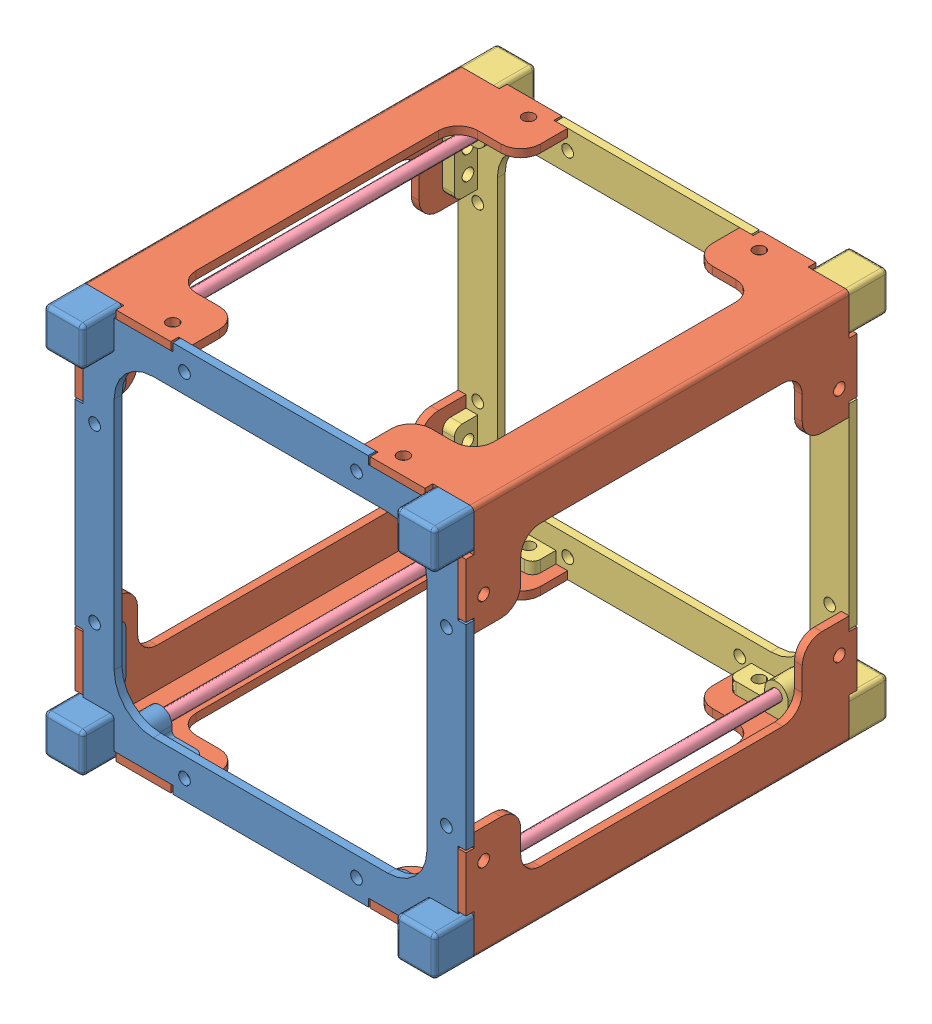
SolidWorks assembly Chassis_1U, configuration Default. Lengths in mm.
Overall size (100 100 116).
10 component instances, 4 part files, 26 mates.
Components (placement in the parent):
- TopPlate-1: TopPlate [Default] at origin size (100 100 16)
- Side Rail-1: Side Rail [Default] at (-50 -48 -96) x (1 0 0) z (0 -1 0) size (28 100 28)
- Side Rail-2: Side Rail [Default] at (48 -50 -96) x (0 1 0) z (1 0 0) size (28 100 28)
- Side Rail-3: Side Rail [Default] at (50 48 -96) x (-1 0 0) z (0 1 0) size (28 100 28)
- Side Rail-4: Side Rail [Default] at (-48 50 -96) x (0 -1 0) z (-1 0 0) size (28 100 28)
- BottomPlate-1: BottomPlate [Default] at (0 0 -96) x (1 0 0) z (0 0 -1) size (100 100 16)
- GuideShaft-1: GuideShaft [Default] at (37.4 -42.85 -96) x (0.813287 0.581862 0) z (0 0 1) size (3 3 96)
- GuideShaft-2: GuideShaft [Default] at (40 42.85 -96) x (0.813287 0.581862 0) z (0 0 1) size (3 3 96)
- GuideShaft-3: GuideShaft [Default] at (-36.2 -42.85 -96) x (0.598556 -0.801081 0) z (0 0 1) size (3 3 96)
- GuideShaft-4: GuideShaft [Default] at (-40 42.85 -96) x (0.069128 0.997608 0) z (0 0 1) size (3 3 96)
Mates (geometry in assembly coordinates):
- Coincident1: coincident aligned: plane of TopPlate-1 through (0 0 0) normal (0 0 1); plane of assembly through (0 0 0) normal (0 0 1)
- Coincident2: coincident aligned: plane of TopPlate-1 through (0 0 0) normal (0 1 0); plane of assembly through (0 0 0) normal (0 1 0)
- Coincident3: coincident aligned: plane of TopPlate-1 through (0 0 0) normal (1 0 0); plane of assembly through (0 0 0) normal (1 0 0)
- Coincident7: coincident aligned: plane of TopPlate-1 through (-25 -50 2) normal (0 -1 0); plane of Side Rail-1 through (-27 -50 -89) normal (0 -1 0)
- Coincident8: coincident aligned: plane of TopPlate-1 through (-49 -49 2) normal (0 0 1); plane of Side Rail-1 through (-39.5 -50 2) normal (0 0 1)
- Coincident9: coincident aligned: plane of TopPlate-1 through (-50 -25 2) normal (-1 0 0); plane of Side Rail-1 through (-50 -50 0) normal (-1 0 0)
- Coincident10: coincident aligned: plane of TopPlate-1 through (-50 -25 2) normal (-1 0 0); plane of Side Rail-4 through (-50 27 -89) normal (-1 0 0)
- Coincident11: coincident aligned: plane of TopPlate-1 through (-25 50 2) normal (0 1 0); plane of Side Rail-4 through (-50 50 0) normal (0 1 0)
- Coincident12: coincident aligned: plane of TopPlate-1 through (-49 -49 2) normal (0 0 1); plane of Side Rail-4 through (-39.5 48 2) normal (0 0 1)
- Coincident13: coincident aligned: plane of TopPlate-1 through (-25 50 2) normal (0 1 0); plane of Side Rail-3 through (27 50 -89) normal (0 1 0)
- Coincident14: coincident aligned: plane of TopPlate-1 through (50 -25 2) normal (1 0 0); plane of Side Rail-3 through (50 50 0) normal (1 0 0)
- Coincident15: coincident aligned: plane of TopPlate-1 through (-49 -49 2) normal (0 0 1); plane of Side Rail-3 through (48 39.5 2) normal (0 0 1)
- Coincident16: coincident aligned: plane of TopPlate-1 through (50 -25 2) normal (1 0 0); plane of Side Rail-2 through (50 -27 -89) normal (1 0 0)
- Coincident17: coincident aligned: plane of TopPlate-1 through (-25 -50 2) normal (0 -1 0); plane of Side Rail-2 through (50 -50 0) normal (0 -1 0)
- Coincident18: coincident aligned: plane of TopPlate-1 through (-49 -49 2) normal (0 0 1); plane of Side Rail-2 through (39.5 -48 2) normal (0 0 1)
- Coincident19: coincident aligned: plane of Side Rail-2 through (50 -27 -89) normal (1 0 0); plane of BottomPlate-1 through (50 25 -98) normal (1 0 0)
- Coincident20: coincident aligned: plane of Side Rail-2 through (50 -50 0) normal (0 -1 0); plane of BottomPlate-1 through (-25 -50 -98) normal (0 -1 0)
- Coincident21: coincident aligned: plane of Side Rail-3 through (39.5 50 -98) normal (0 0 -1); plane of BottomPlate-1 through (-49 49 -98) normal (0 0 -1)
- Concentric1: concentric anti-aligned: cylinder of TopPlate-1 through (37.4 -42.85 -6) axis (0 0 1) radius 1.5; cylinder of GuideShaft-1 through (37.4 -42.85 0) axis (0 0 -1) radius 1.5
- Coincident22: coincident anti-aligned: plane of TopPlate-1 through (-49 -49 0) normal (0 0 -1); plane of GuideShaft-1 through (37.4 -42.85 0) normal (0 0 1)
- Concentric2: concentric anti-aligned: cylinder of TopPlate-1 through (-36.2 -42.85 -6) axis (0 0 1) radius 1.5; cylinder of GuideShaft-3 through (-36.2 -42.85 0) axis (0 0 -1) radius 1.5
- Coincident23: coincident anti-aligned: plane of TopPlate-1 through (-49 -49 0) normal (0 0 -1); plane of GuideShaft-3 through (-36.2 -42.85 0) normal (0 0 1)
- Concentric3: concentric anti-aligned: cylinder of TopPlate-1 through (40 42.85 -6) axis (0 0 1) radius 1.5; cylinder of GuideShaft-2 through (40 42.85 0) axis (0 0 -1) radius 1.5
- Coincident24: coincident anti-aligned: plane of TopPlate-1 through (-49 -49 0) normal (0 0 -1); plane of GuideShaft-2 through (40 42.85 0) normal (0 0 1)
- Concentric4: concentric anti-aligned: cylinder of TopPlate-1 through (-40 42.85 -6) axis (0 0 1) radius 1.5; cylinder of GuideShaft-4 through (-40 42.85 0) axis (0 0 -1) radius 1.5
- Coincident25: coincident anti-aligned: plane of TopPlate-1 through (-49 -49 0) normal (0 0 -1); plane of GuideShaft-4 through (-40 42.85 0) normal (0 0 1)
